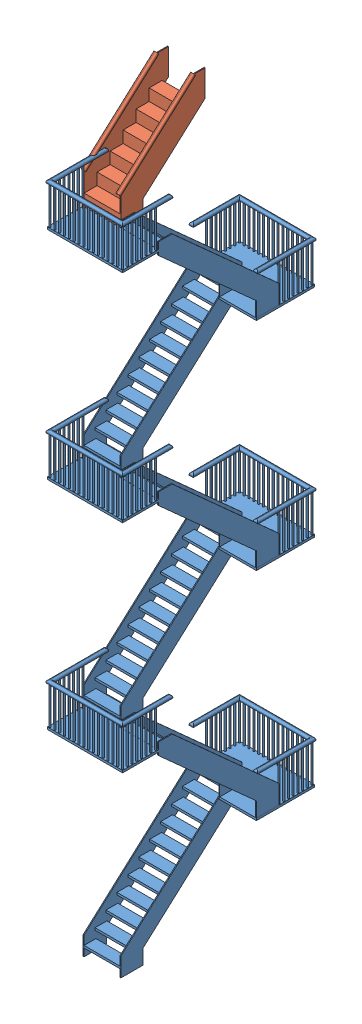
SolidWorks assembly Stairs ASSY, configuration Default. Lengths in mm.
Overall size (1730 16701.93 4317.68).
7 component instances, 2 part files, 18 mates.
Components (placement in the parent):
- Stairs-1: Stairs [Default] at (-414.0766 -1291.1166 -7739.3822) size (1710 3327.63 3502.68)
- Stairs-3: Stairs [Default] at (1225.9234 1126.5117 8564.4095) x (-1 0 0) z (0 0 -1) size (1710 3327.63 3502.68)
- Stairs-4: Stairs [Default] at (-414.0766 3544.14 -7739.3822) size (1710 3327.63 3502.68)
- Stairs-5: Stairs [Default] at (-414.0766 8379.3966 -7739.3822) size (1710 3327.63 3502.68)
- Stairs-6: Stairs [Default] at (1225.9234 5961.7683 8564.4095) x (-1 0 0) z (0 0 -1) size (1710 3327.63 3502.68)
- Stairs-7: Stairs [Default] at (1225.9234 10797.0249 8564.4095) x (-1 0 0) z (0 0 -1) size (1710 3327.63 3502.68)
- Small Stairs-1: Small Stairs [Default] at (385.9234 13214.6532 1756.3548) x (-1 0 0) z (0 0 -1) size (910 2196.16 1960.05)
Mates (geometry in assembly coordinates):
- Coincident3: coincident anti-aligned: plane of Stairs-1 through (405.9234 -1291.1166 -7739.3822) normal (1 0 0); plane of Stairs-3 through (405.9234 1126.5117 8564.4095) normal (-1 0 0)
- Coincident4: coincident anti-aligned: plane of Stairs-1 through (405.9234 1126.5117 -1731.3275) normal (0 1 0); plane of Stairs-3 through (1245.9234 1126.5117 -431.3275) normal (0 -1 0)
- Coincident5: coincident aligned: plane of Stairs-1 through (-434.0766 1276.1453 -931.3275) normal (0 0 -1); plane of Stairs-3 through (405.9234 1548.3566 -931.3275) normal (0 0 -1)
- Coincident6: coincident anti-aligned: plane of Stairs-3 through (405.9234 1126.5117 8564.4095) normal (-1 0 0); plane of Stairs-4 through (405.9234 3544.14 -7739.3822) normal (1 0 0)
- Coincident7: coincident anti-aligned: plane of Stairs-3 through (405.9234 3544.14 2556.3548) normal (0 1 0); plane of Stairs-4 through (-434.0766 3544.14 1256.3548) normal (0 -1 0)
- Coincident8: coincident aligned: plane of Stairs-3 through (1245.9234 3693.7736 1756.3548) normal (0 0 1); plane of Stairs-4 through (405.9234 3965.9849 1756.3548) normal (0 0 1)
- Coincident9: coincident anti-aligned: plane of Stairs-4 through (405.9234 5961.7683 -1731.3275) normal (0 1 0); plane of Stairs-6 through (405.9234 5961.7683 -431.3275) normal (0 -1 0)
- Coincident10: coincident anti-aligned: plane of Stairs-4 through (405.9234 3544.14 -7739.3822) normal (1 0 0); plane of Stairs-6 through (405.9234 5961.7683 8564.4095) normal (-1 0 0)
- Coincident11: coincident aligned: plane of Stairs-4 through (-434.0766 6111.4019 -931.3275) normal (0 0 -1); plane of Stairs-6 through (405.9234 6383.6132 -931.3275) normal (0 0 -1)
- Coincident12: coincident anti-aligned: plane of Stairs-5 through (405.9234 8379.3966 -7739.3822) normal (1 0 0); plane of Stairs-6 through (405.9234 5961.7683 8564.4095) normal (-1 0 0)
- Coincident13: coincident anti-aligned: plane of Stairs-5 through (-434.0766 8379.3966 1256.3548) normal (0 -1 0); plane of Stairs-6 through (405.9234 8379.3966 2556.3548) normal (0 1 0)
- Coincident14: coincident aligned: plane of Stairs-5 through (-434.0766 8713.1905 1256.3548) normal (0 0 -1); plane of Stairs-6 through (1225.9234 5961.7683 1256.3548) normal (0 0 -1)
- Coincident15: coincident anti-aligned: plane of Stairs-5 through (405.9234 8379.3966 -7739.3822) normal (1 0 0); plane of Stairs-7 through (405.9234 10797.0249 8564.4095) normal (-1 0 0)
- Coincident16: coincident anti-aligned: plane of Stairs-5 through (405.9234 10797.0249 -1731.3275) normal (0 1 0); plane of Stairs-7 through (1245.9234 10797.0249 -431.3275) normal (0 -1 0)
- Coincident17: coincident aligned: plane of Stairs-5 through (-414.0766 8379.3966 -431.3275) normal (0 0 1); plane of Stairs-7 through (1245.9234 11130.8188 -431.3275) normal (0 0 1)
- Coincident19: coincident anti-aligned: plane of Stairs-7 through (405.9234 13214.6532 2556.3548) normal (0 1 0); plane of Small Stairs-1 through (-414.0766 13214.6532 1736.3548) normal (0 -1 0)
- Coincident20: coincident aligned: plane of Stairs-7 through (1225.9234 10797.0249 1256.3548) normal (0 0 -1); plane of Small Stairs-1 through (-434.0766 13214.6532 1256.3548) normal (0 0 -1)
- Coincident21: coincident anti-aligned: plane of Stairs-7 through (405.9234 10797.0249 8564.4095) normal (-1 0 0); plane of Small Stairs-1 through (405.9234 13214.6532 1756.3548) normal (1 0 0)
